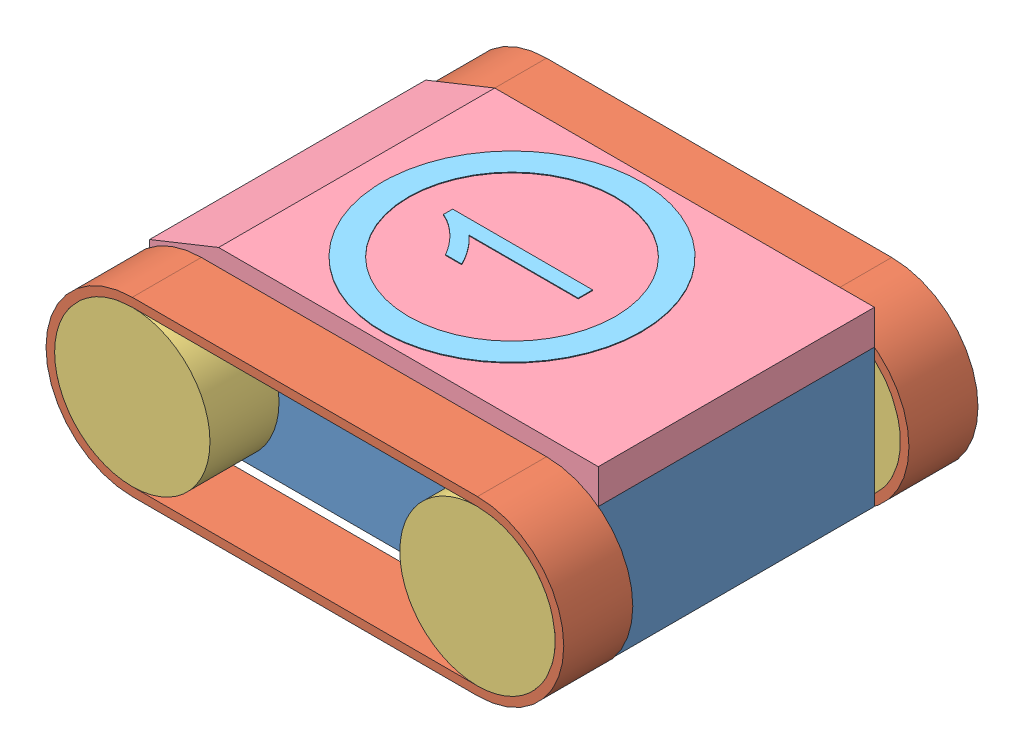
SolidWorks assembly robot_base, configuration Default. Lengths in mm.
Overall size (150 55.2 120).
9 component instances, 5 part files, 21 mates.
Components (placement in the parent):
- body-1: body [Default] at origin size (130 40 80)
- track-1: track [Default] at (0 20 -60) size (150 50 20)
- track-2: track [Default] at (0 20 40) size (150 50 20)
- wheel-1: wheel [Default] at (-50 20 40) size (45 45 20)
- wheel-2: wheel [Default] at (50 20 40) size (45 45 20)
- wheel-3: wheel [Default] at (-50 20 -60) size (45 45 20)
- wheel-4: wheel [Default] at (50 20 -60) size (45 45 20)
- top-1: top [Default] at (0 40 0) x (-1 0 0) z (0 0 -1) size (130 10 80)
- Part1^robot_base-1: Part1^robot_base [Default] at (0 50 0) x (-1 0 0) z (0 1 0) size (75 75 0.2) (virtual)
Mates (geometry in assembly coordinates):
- Coincident1: coincident anti-aligned: plane of body-1 through (-65 40 -40) normal (0 0 -1); plane of track-1 through (-50 20 -40) normal (0 0 1)
- Coincident2: coincident aligned: plane of track-1 through (0 20 -60) normal (1 0 0)
- Coincident4: coincident aligned: plane of body-1 through (0 20 0) normal (0 1 0); plane of track-1 through (0 20 -60) normal (0 1 0)
- Coincident5: coincident anti-aligned: plane of body-1 through (-65 40 40) normal (0 0 1); plane of track-2 through (-50 20 40) normal (0 0 -1)
- Coincident6: coincident aligned: plane of body-1 through (0 0 0) normal (1 0 0); plane of track-2 through (0 20 40) normal (1 0 0)
- Coincident7: coincident aligned: plane of body-1 through (0 20 0) normal (0 1 0); plane of track-2 through (0 20 40) normal (0 1 0)
- Coincident8: coincident anti-aligned: plane of body-1 through (-65 40 40) normal (0 0 1); plane of wheel-1 through (-50 20 40) normal (0 0 -1)
- Coincident9: coincident aligned: circle of track-2; circle of wheel-1
- Coincident10: coincident anti-aligned: plane of body-1 through (-65 40 40) normal (0 0 1); plane of wheel-2 through (50 20 40) normal (0 0 -1)
- Coincident11: coincident aligned: circle of track-2; circle of wheel-2
- Coincident12: coincident anti-aligned: plane of body-1 through (-65 40 -40) normal (0 0 -1); plane of wheel-4 through (50 20 -40) normal (0 0 1)
- Coincident13: coincident anti-aligned: plane of body-1 through (-65 40 -40) normal (0 0 -1); plane of wheel-3 through (-50 20 -40) normal (0 0 1)
- Coincident14: coincident aligned: circle of track-1; circle of wheel-4
- Coincident15: coincident aligned: circle of track-1; circle of wheel-3
- Coincident16: coincident anti-aligned: plane of body-1 through (0 40 0) normal (0 1 0); plane of top-1 through (0 40 0) normal (0 -1 0)
- Coincident17: coincident aligned: plane of body-1 through (-65 40 40) normal (-1 0 0); plane of top-1 through (-65 50 -40) normal (-1 0 0)
- Coincident18: coincident aligned: plane of body-1 through (-65 40 -40) normal (0 0 -1); plane of top-1 through (65 50 -40) normal (0 0 -1)
- InPlace1: in place: plane of top-1 through (0 50 0) normal (0 1 0); plane of ? through (0 50 0) normal (0 1 0); moOrthogonalPlaneRef_w of top-1 through (0 50 0) normal (0 1 0); plane of ? through (0 50 0) normal (0 0 -1); plane of top-1 through (0 50 0) normal (0 1 0); plane of ? through (0 50 0) normal (1 0 0); plane of top-1 through (0 50 0) normal (0 1 0); unknown of Part1^robot_base-1
- Coincident19: coincident aligned: plane of top-1 through (0 50 0) normal (0 1 0); plane of Part1^robot_base-1 through (0 50 0) normal (0 1 0)
- Coincident20: coincident aligned: moOrthogonalPlaneRef_w of top-1 through (0 50 0) normal (0 0 1); plane of Part1^robot_base-1 through (0 50 0) normal (0 0 1)
- Coincident21: coincident anti-aligned: moOrthogonalPlaneRef_w of top-1 through (0 50 0) normal (1 0 0); plane of Part1^robot_base-1 through (0 50 0) normal (-1 0 0)
